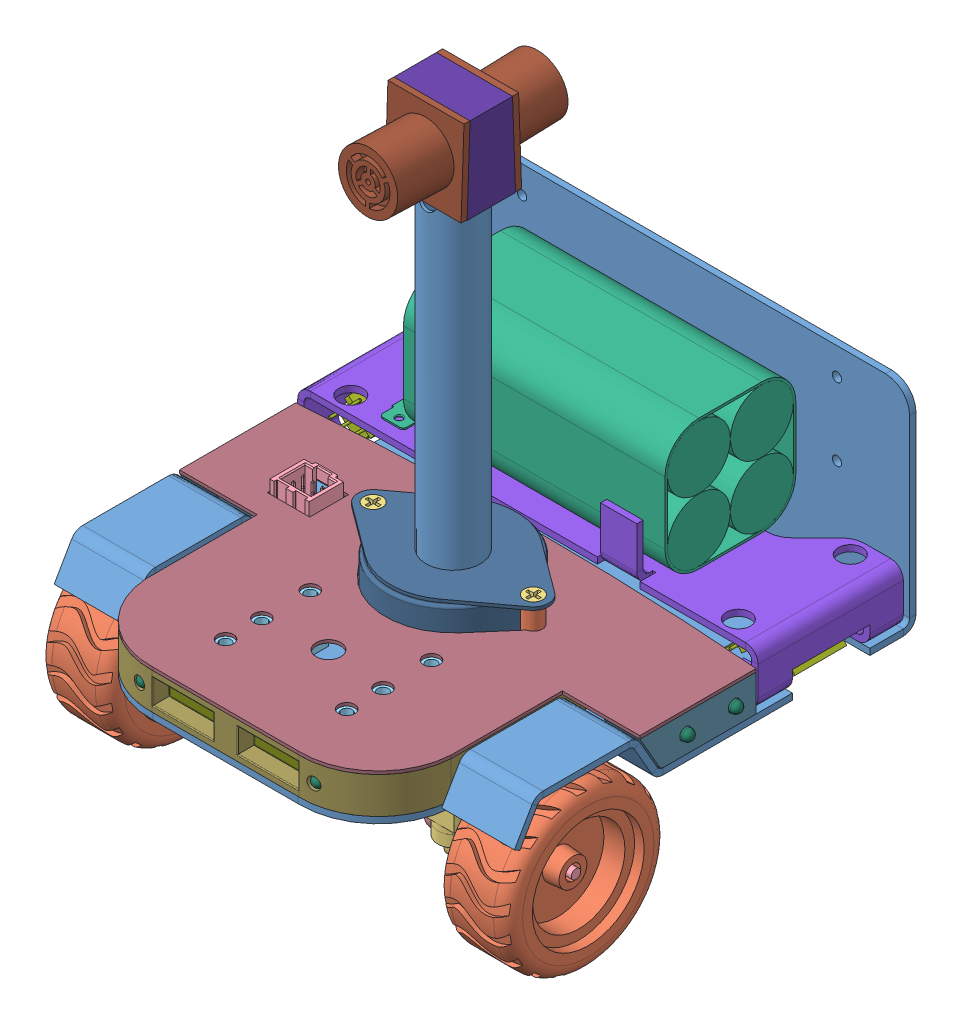
SolidWorks assembly REAR, TOP LEVEL, configuration Default. Lengths in mm.
Overall size (124.43 158.23 120.66).
44 component instances, 24 part files, 91 mates.
Components (placement in the parent):
- PLATE, REAR-1: PLATE, REAR [Default] at (-42.1312 28.0774 12.7174) size (120.65 55.63 120.66)
- WHEEL ASSEMBLY-1: WHEEL ASSEMBLY [Default-_flexible1] at (7.6153 26.9792 58.7651) x (0 0 1) z (1 0 0) size (42.46 78.6 70.03) (flexible)
  - Pololu 49x19 Wheel-1: Pololu 49x19 Wheel [Default] at (-19.8703 11.8393 2.4418) size (42.46 42.56 19)
  - Pololu Extended Micro Metal Bracket-1: Pololu Extended Micro Metal Bracket [Default] at (-19.8703 6.8393 -18.4366) size (26.6 22.49 26.04)
  - Pololu 298-1 Motor-1: Pololu 298-1 Motor [Default] at (-19.8703 11.8393 -25.1366) x (0 0 -1) z (0 1 0) size (35.87 12 10)
- WHEEL ASSEMBLY-2: WHEEL ASSEMBLY [Default-_flexible2] at (-91.8778 26.9792 19.0244) x (0 0 -1) z (-1 0 0) size (42.46 78.6 70.03) (flexible)
  - Pololu 49x19 Wheel-1: Pololu 49x19 Wheel [Default] at (-19.8703 11.8393 2.4418) size (42.46 42.56 19)
  - Pololu Extended Micro Metal Bracket-1: Pololu Extended Micro Metal Bracket [Default] at (-19.8703 6.8393 -18.4366) size (26.6 22.49 26.04)
  - Pololu 298-1 Motor-1: Pololu 298-1 Motor [Default] at (-19.8703 11.8393 -25.1366) x (0 0 -1) z (0 1 0) size (35.87 12 10)
- Socket Head Cap Screw_AI-1: Socket Head Cap Screw_AI [HX-SHCS 0.086-56x0.4375x0.4375-N] at (-77.6912 31.9128 47.8948) x (0 -1 0) z (-0.381305 0 -0.924449) size (13.3 3.56 3.56)
- Socket Head Cap Screw_AI-2: Socket Head Cap Screw_AI [HX-SHCS 0.086-56x0.4375x0.4375-N] at (-77.6912 31.9128 29.8948) x (0 -1 0) z (0 0 1) size (13.3 3.56 3.56)
- Socket Head Cap Screw_AI-3: Socket Head Cap Screw_AI [HX-SHCS 0.086-56x0.4375x0.4375-N] at (-6.5712 31.9128 29.8948) x (0 -1 0) z (0 0 1) size (13.3 3.56 3.56)
- Socket Head Cap Screw_AI-4: Socket Head Cap Screw_AI [HX-SHCS 0.086-56x0.4375x0.4375-N] at (-6.5712 31.9128 47.8948) x (0 -1 0) z (0 0 1) size (13.3 3.56 3.56)
- 4000mAh 7.4V Battery Pack-1: 4000mAh 7.4V Battery Pack [Default] at (-42.1312 61.2244 -25.7652) x (0 0 -1) z (1 0 0) size (34.29 34.29 68.58)
- SENSOR, GP2Y0D810-1: SENSOR, GP2Y0D810 [Default] at (9.9271 36.6454 -23.9419) x (0 0 -1) z (0.766044 0.642788 0) size (28.32 10.54 8.89)
- SENSOR, GP2Y0D810-2: SENSOR, GP2Y0D810 [Default] at (-94.1896 36.6454 -23.9419) x (0 0 -1) z (0.766044 -0.642788 0) size (28.32 10.54 8.89)
- Battery Support-1: Battery Support [Default] at (-42.1312 29.7284 -26.0192) size (120.65 27.05 38.1)
- Mounting Block-1: Mounting Block [Default] at (-42.1312 36.0784 -35.6712) x (-1 0 0) z (0 0 -1) size (25.4 12.7 25.4)
- PF35T-48-1: PF35T-48 [Default] at (-42.1312 31.7284 12.5888) size (50 29.2 35)
- MaxSonar EZ1-1: MaxSonar EZ1 [Default] at (-42.1312 140.4691 6.6293) x (-1 0 0) z (0 0.034899 -0.999391) size (19.94 22.1 16.38)
- MaxSonar EZ1-2: MaxSonar EZ1 [Default] at (-42.1312 140.4691 18.5483) x (1 0 0) z (0 0.034899 0.999391) size (19.94 22.1 16.38)
- BUMPER, REAR-1: BUMPER, REAR [Default] at (-42.1312 29.7284 53.2288) x (-1 0 0) z (0 0 -1) size (80.01 9.53 54.3)
- PLATE, REAR COVER-1: PLATE, REAR COVER [Default] at (-42.1312 39.2534 72.2788) size (120.65 0.81 81.14)
- MOUNTING BLOCK, COLOR SENSOR-1: MOUNTING BLOCK, COLOR SENSOR [Default] at (-97.6937 29.7284 5.6038) size (9.53 9.53 30.46)
- MOUNTING BLOCK, COLOR SENSOR-2: MOUNTING BLOCK, COLOR SENSOR [Default] at (13.4313 29.7284 5.6038) size (9.53 9.53 30.46)
- SENSOR, COLOR LED-1: SENSOR, COLOR LED [Default] at (-24.0807 23.782 31.9371) x (0 0 -1) z (-0.409692 -0.912224 0) size (5.83 3.66 3.66)
- SENSOR, COLOR LED-2: SENSOR, COLOR LED [Default] at (-67.3741 22.996 31.9371) x (0 0 -1) z (-0.202984 -0.979182 0) size (5.83 3.66 3.66)
- COPPER CONTACT-1: COPPER CONTACT [Default] at (-53.2437 34.4909 64.0238) size (15.88 6.35 4.45)
- COPPER CONTACT-2: COPPER CONTACT [Default] at (-31.0187 34.4909 64.0238) size (15.88 6.35 4.45)
- MOUNTING BLOCK, SONAR-1: MOUNTING BLOCK, SONAR [Default] at (-42.1312 140.3989 12.5888) x (-1 0 0) z (0 0 -1) size (19.94 22.23 12.7)
- SHAFT, SONAR MOUNT-1: SHAFT, SONAR MOUNT [Default] at (-42.1312 52.5784 12.5888) x (-0.538443 0 0.842662) z (-0.842662 0 -0.538443) size (4.76 89.41 4.76)
- SHAFT, SONAR SUPPORT-1: SHAFT, SONAR SUPPORT [Default] at (-42.1312 46.7284 12.5888) x (0.999987 0 0.005105) z (-0.005105 0 0.999987) size (14.22 82.87 14.22)
- SHAFT, STEPPER SUPPORT-1: SHAFT, STEPPER SUPPORT [Default] at (-63.1312 29.6724 12.5888) size (4.76 16.26 4.76)
- SHAFT, STEPPER SUPPORT-2: SHAFT, STEPPER SUPPORT [Default] at (-21.1312 29.6724 12.5888) x (0.987866 0 -0.155311) z (0.155311 0 0.987866) size (4.76 16.26 4.76)
- Flat Head 100 Screw_AI-2: Flat Head 100 Screw_AI [CR-FHM1 0.112-40x0.25x0.25-N] at (-63.1312 46.7284 12.5888) x (0 -1 0) z (0 0 1) size (6.35 4.85 4.85)
- Flat Head 100 Screw_AI-3: Flat Head 100 Screw_AI [CR-FHM1 0.112-40x0.25x0.25-N] at (-21.1312 46.7284 12.5888) x (0 -1 0) z (0 0 1) size (6.35 4.85 4.85)
- CONNECTOR, MOLEX 6 PIN-1: CONNECTOR, MOLEX 6 PIN [Default] at (-80.2263 37.7912 12.5433) size (10.34 13.8 9.75)
- SENSOR, COLOR LED-3: SENSOR, COLOR LED [Default] at (-64.0196 42.7147 3.5765) x (1 0 0) z (0 0.700538 -0.713616) size (5.83 3.66 3.66)
- SENSOR, COLOR LED-4: SENSOR, COLOR LED [Default] at (-64.0196 42.7147 -9.1235) x (1 0 0) z (0 0.700538 -0.713616) size (5.83 3.66 3.66)
- SENSOR, COLOR LED-5: SENSOR, COLOR LED [Default] at (-20.2429 42.7147 20.3311) x (-1 0 0) z (0 0.700538 0.713616) size (5.83 3.66 3.66)
- SENSOR, COLOR LED-6: SENSOR, COLOR LED [Default] at (-20.2429 42.7147 7.6311) x (-1 0 0) z (0 0.700538 0.713616) size (5.83 3.66 3.66)
- MOUNTING BLOCK, REAR-1: MOUNTING BLOCK, REAR [Default] at (-58.0062 34.4909 31.0038) size (9.53 9.53 28.57)
- MOUNTING BLOCK, REAR-2: MOUNTING BLOCK, REAR [Default] at (-26.2562 34.4909 31.0038) size (9.53 9.53 28.57)
- SW3dPS-Sliderswitch-1: SW3dPS-Sliderswitch [Standard] at (-81.1109 44.0794 -21.7288) size (7.4 16 23.2)
Mates (geometry in assembly coordinates):
- Coincident1: coincident aligned: plane of WHEEL ASSEMBLY-1/Pololu Extended Micro Metal Bracket-1 through (6.4788 20.1399 25.5948) normal (0 1 0); plane of WHEEL ASSEMBLY-2/Pololu Extended Micro Metal Bracket-1 through (-90.7412 20.1399 52.1948) normal (0 1 0)
- Coincident2: coincident anti-aligned: plane of PLATE, REAR-1 through (-82.1362 28.0774 18.9388) normal (0 -1 0); plane of WHEEL ASSEMBLY-2/Pololu Extended Micro Metal Bracket-1 through (-66.7356 28.0774 52.1948) normal (0 1 0)
- Coincident3: coincident aligned: plane of Socket Head Cap Screw_AI-1 through (-77.6912 31.9128 47.8948) normal (0 1 0); plane of Socket Head Cap Screw_AI-2 through (-77.6912 31.9128 29.8948) normal (0 1 0)
- Coincident4: coincident aligned: plane of Socket Head Cap Screw_AI-3 through (-6.5712 31.9128 29.8948) normal (0 1 0); plane of Socket Head Cap Screw_AI-4 through (-6.5712 31.9128 47.8948) normal (0 1 0)
- Coincident5: coincident aligned: plane of Socket Head Cap Screw_AI-2 through (-77.6912 31.9128 29.8948) normal (0 1 0); plane of Socket Head Cap Screw_AI-3 through (-6.5712 31.9128 29.8948) normal (0 1 0)
- Coincident6: coincident anti-aligned: plane of PLATE, REAR-1 through (-82.1362 29.7284 18.9388) normal (0 1 0); plane of Socket Head Cap Screw_AI-3 through (-4.7932 29.7284 29.8948) normal (0 -1 0)
- Concentric6: concentric aligned: cylinder of PLATE, REAR-1; cylinder of Socket Head Cap Screw_AI-2
- Concentric7: concentric aligned: cylinder of PLATE, REAR-1; cylinder of Socket Head Cap Screw_AI-1
- Concentric8: concentric aligned: cylinder of PLATE, REAR-1; cylinder of Socket Head Cap Screw_AI-3
- Concentric9: concentric aligned: cylinder of PLATE, REAR-1; cylinder of Socket Head Cap Screw_AI-4
- Concentric40: concentric aligned: cylinder of WHEEL ASSEMBLY-2/Pololu Extended Micro Metal Bracket-1; cylinder of Socket Head Cap Screw_AI-2
- Concentric41: concentric aligned: cylinder of WHEEL ASSEMBLY-2/Pololu Extended Micro Metal Bracket-1; cylinder of Socket Head Cap Screw_AI-1
- Concentric42: concentric aligned: cylinder of WHEEL ASSEMBLY-1/Pololu Extended Micro Metal Bracket-1; cylinder of Socket Head Cap Screw_AI-3
- Concentric43: concentric aligned: cylinder of WHEEL ASSEMBLY-1/Pololu Extended Micro Metal Bracket-1; cylinder of Socket Head Cap Screw_AI-4
- Coincident91: coincident aligned: plane of PLATE, REAR-1 through (-42.1312 28.0774 12.7174) normal (1 0 0); plane of 4000mAh 7.4V Battery Pack-1 through (-42.1312 61.2244 -25.7652) normal (1 0 0)
- Concentric44: concentric: cylinder of PLATE, REAR-1; cylinder of SENSOR, GP2Y0D810-2
- Parallel1: parallel: plane of PLATE, REAR-1 through (-97.7091 37.4434 -30.9045) normal (0 0 1); plane of SENSOR, GP2Y0D810-2 through (-89.7641 35.0043 -35.8291) normal (0 0 -1)
- Coincident93: coincident anti-aligned: plane of PLATE, REAR-1 through (1.6838 29.7284 -30.9045) normal (-0.642788 0.766044 0); plane of SENSOR, GP2Y0D810-1 through (6.522 33.7882 -35.8291) normal (0.642788 -0.766044 0)
- Concentric45: concentric aligned: cylinder of PLATE, REAR-1; cylinder of SENSOR, GP2Y0D810-1
- Parallel2: parallel aligned: plane of SENSOR, GP2Y0D810-1 through (12.3118 40.7187 -14.3661) normal (0.766044 0.642788 0); plane of PLATE, REAR-1 through (13.4467 37.4434 -35.9845) normal (0.766044 0.642788 0)
- Coincident97: coincident anti-aligned: plane of PLATE, REAR-1 through (-82.1362 29.7284 18.9388) normal (0 1 0); plane of Battery Support-1 through (18.1938 29.7284 -6.9692) normal (0 -1 0)
- Coincident98: coincident aligned: plane of PLATE, REAR-1 through (-42.1312 28.0774 12.7174) normal (1 0 0); plane of Battery Support-1 through (-42.1312 29.7284 -26.0192) normal (1 0 0)
- Coincident100: coincident aligned: plane of Battery Support-1 through (-89.7562 33.0304 -36.3062) normal (0 0 1); plane of PLATE, REAR-1 through (-102.4562 28.0774 -36.3062) normal (0 0 1)
- Coincident101: coincident anti-aligned: plane of 4000mAh 7.4V Battery Pack-1 through (-76.4212 69.4794 -8.6202) normal (0 0 1); plane of Battery Support-1 through (-23.0812 44.0794 -8.6202) normal (0 0 -1)
- Coincident102: coincident anti-aligned: plane of 4000mAh 7.4V Battery Pack-1 through (-76.4212 44.0794 -17.5102) normal (0 -1 0); plane of Battery Support-1 through (-102.4562 44.0794 -6.9692) normal (0 1 0)
- Coincident103: coincident anti-aligned: plane of PLATE, REAR-1 through (-82.1362 29.7284 18.9388) normal (0 1 0); plane of Mounting Block-1 through (-29.4312 29.7284 -48.3712) normal (0 -1 0)
- Concentric46: concentric aligned: cylinder of PLATE, REAR-1; cylinder of Mounting Block-1
- Concentric54: concentric aligned: cylinder of PLATE, REAR-1; cylinder of Mounting Block-1
- Coincident104: coincident anti-aligned: plane of PLATE, REAR-1 through (-82.1362 29.7284 18.9388) normal (0 1 0); plane of PF35T-48-1 through (-42.1312 29.7284 12.5888) normal (0 -1 0)
- Coincident105: coincident anti-aligned: plane of PLATE, REAR-1 through (-82.1362 29.7284 18.9388) normal (0 1 0); plane of BUMPER, REAR-1 through (-22.4072 29.7284 51.97) normal (0 -1 0)
- Coincident107: coincident aligned: plane of PLATE, REAR-1 through (-61.1812 28.0774 72.2788) normal (0 0 1); plane of BUMPER, REAR-1 through (-23.0812 39.2534 72.2788) normal (0 0 1)
- Concentric57: concentric anti-aligned: cylinder of PLATE, REAR-1; cylinder of BUMPER, REAR-1
- Coincident108: coincident anti-aligned: plane of BUMPER, REAR-1 through (-22.4072 39.2534 51.97) normal (0 1 0); plane of PLATE, REAR COVER-1 through (-61.8553 39.2534 51.97) normal (0 -1 0)
- Coincident109: coincident aligned: plane of PLATE, REAR-1 through (-61.1812 28.0774 72.2788) normal (0 0 1); plane of PLATE, REAR COVER-1 through (-23.0812 40.0662 72.2788) normal (0 0 1)
- Concentric58: concentric anti-aligned: cylinder of PLATE, REAR-1; cylinder of PLATE, REAR COVER-1
- Concentric59: concentric anti-aligned: cylinder of PF35T-48-1; cylinder of PLATE, REAR COVER-1
- Coincident110: coincident aligned: plane of MOUNTING BLOCK, COLOR SENSOR-1 through (-92.9312 39.2534 -6.4612) normal (0 1 0); plane of MOUNTING BLOCK, COLOR SENSOR-2 through (18.1938 39.2534 -6.4612) normal (0 1 0)
- Coincident111: coincident anti-aligned: plane of PLATE, REAR-1 through (-82.1362 29.7284 18.9388) normal (0 1 0); plane of MOUNTING BLOCK, COLOR SENSOR-1 through (-92.9312 29.7284 -6.4612) normal (0 -1 0)
- Coincident112: coincident aligned: plane of MOUNTING BLOCK, COLOR SENSOR-1 through (-102.4562 39.2534 -6.4612) normal (0 0 -1); plane of MOUNTING BLOCK, COLOR SENSOR-2 through (8.6688 39.2534 -6.4612) normal (0 0 -1)
- Coincident113: coincident: line of PLATE, REAR-1; plane of MOUNTING BLOCK, COLOR SENSOR-1 through (-102.4562 39.2534 17.6688) normal (-1 0 0)
- Coincident114: coincident aligned: plane of PLATE, REAR-1 through (18.1938 29.7284 18.9388) normal (1 0 0); plane of MOUNTING BLOCK, COLOR SENSOR-2 through (18.1938 39.2534 17.6688) normal (1 0 0)
- Coincident115: coincident aligned: line of MOUNTING BLOCK, COLOR SENSOR-2; line of PLATE, REAR COVER-1
- Concentric60: concentric anti-aligned: cylinder of PF35T-48-1; cylinder of PLATE, REAR COVER-1
- Coincident117: coincident aligned: plane of MaxSonar EZ1-1 through (-52.1007 129.4822 4.6572) normal (-1 0 0); plane of MaxSonar EZ1-2 through (-52.1007 129.4822 20.5204) normal (-1 0 0)
- Concentric62: concentric aligned: cylinder of BUMPER, REAR-1; cylinder of SENSOR, COLOR LED-1
- Concentric63: concentric aligned: cylinder of BUMPER, REAR-1; cylinder of SENSOR, COLOR LED-2
- Coincident120: coincident aligned: plane of COPPER CONTACT-1 through (-45.3062 37.6659 68.4688) normal (0 0 1); plane of COPPER CONTACT-2 through (-23.0812 37.6659 68.4688) normal (0 0 1)
- Coincident121: coincident aligned: plane of COPPER CONTACT-1 through (-61.1812 37.6659 68.4688) normal (0 1 0); plane of COPPER CONTACT-2 through (-38.9562 37.6659 68.4688) normal (0 1 0)
- Coincident122: coincident anti-aligned: plane of BUMPER, REAR-1 through (-38.9562 31.3159 72.29) normal (0 1 0); plane of COPPER CONTACT-2 through (-38.9562 31.3159 68.4688) normal (0 -1 0)
- Coincident123: coincident anti-aligned: plane of BUMPER, REAR-1 through (-23.0812 31.3159 72.29) normal (-1 0 0); plane of COPPER CONTACT-2 through (-23.0812 31.3159 68.4688) normal (1 0 0)
- Coincident124: coincident anti-aligned: plane of BUMPER, REAR-1 through (-61.1812 31.3159 72.29) normal (1 0 0); plane of COPPER CONTACT-1 through (-61.1812 31.3159 68.4688) normal (-1 0 0)
- Distance3: distance = 3.81 mm aligned: plane of COPPER CONTACT-2 through (-23.0812 37.6659 68.4688) normal (0 0 1); plane of BUMPER, REAR-1 through (-23.0812 39.2534 72.2788) normal (0 0 1)
- Coincident125: coincident anti-aligned: plane of MaxSonar EZ1-1 through (-52.1007 151.5114 7.0149) normal (0 -0.034899 0.999391); plane of MOUNTING BLOCK, SONAR-1 through (-32.1617 129.2864 6.2388) normal (0 0.034899 -0.999391)
- Coincident126: coincident aligned: plane of MaxSonar EZ1-1 through (-52.1007 129.4822 4.6572) normal (-1 0 0); plane of MOUNTING BLOCK, SONAR-1 through (-52.1007 129.2864 6.2388) normal (-1 0 0)
- Concentric64: concentric aligned: cylinder of PF35T-48-1; cylinder of MOUNTING BLOCK, SONAR-1
- Coincident129: coincident anti-aligned: plane of PF35T-48-1 through (-42.1312 58.9284 12.5888) normal (0 1 0); plane of SHAFT, SONAR MOUNT-1 through (-42.1312 58.9284 12.5888) normal (0 -1 0)
- Concentric65: concentric aligned: cylinder of PF35T-48-1; cylinder of SHAFT, SONAR MOUNT-1
- Concentric66: concentric aligned: cylinder of SHAFT, SONAR MOUNT-1; cylinder of SHAFT, SONAR SUPPORT-1
- Coincident130: coincident anti-aligned: plane of PF35T-48-1 through (-63.1312 46.7284 12.5888) normal (0 1 0); plane of SHAFT, SONAR SUPPORT-1 through (-42.1312 46.7284 12.5888) normal (0 -1 0)
- Concentric67: concentric anti-aligned: cylinder of PLATE, REAR COVER-1; cylinder of SHAFT, STEPPER SUPPORT-1
- Concentric68: concentric anti-aligned: cylinder of PLATE, REAR COVER-1; cylinder of SHAFT, STEPPER SUPPORT-2
- Coincident131: coincident anti-aligned: plane of PF35T-48-1 through (-63.1312 45.9284 12.5888) normal (0 -1 0); plane of SHAFT, STEPPER SUPPORT-1 through (-63.1312 45.9284 12.5888) normal (0 1 0)
- Coincident132: coincident anti-aligned: plane of PF35T-48-1 through (-63.1312 45.9284 12.5888) normal (0 -1 0); plane of SHAFT, STEPPER SUPPORT-2 through (-21.1312 45.9284 12.5888) normal (0 1 0)
- Coincident133: coincident aligned: plane of Flat Head 100 Screw_AI-2 through (-61.7088 40.3784 12.5888) normal (0 -1 0); plane of Flat Head 100 Screw_AI-3 through (-19.7088 40.3784 12.5888) normal (0 -1 0)
- Concentric69: concentric anti-aligned: cylinder of SHAFT, STEPPER SUPPORT-2; cylinder of Flat Head 100 Screw_AI-3
- Concentric70: concentric anti-aligned: cylinder of SHAFT, STEPPER SUPPORT-1; cylinder of Flat Head 100 Screw_AI-2
- Coincident134: coincident aligned: plane of PF35T-48-1 through (-63.1312 46.7284 12.5888) normal (0 1 0); plane of Flat Head 100 Screw_AI-2 through (-63.1312 46.7284 12.5888) normal (0 1 0)
- Coincident135: coincident aligned: plane of SENSOR, COLOR LED-3 through (-98.5192 37.1081 11.9296) normal (1 0 0); plane of SENSOR, COLOR LED-4 through (-98.5192 37.1081 -0.7704) normal (1 0 0)
- Coincident136: coincident aligned: plane of SENSOR, COLOR LED-5 through (14.2568 37.1081 11.978) normal (-1 0 0); plane of SENSOR, COLOR LED-6 through (14.2568 37.1081 -0.722) normal (-1 0 0)
- Concentric71: concentric anti-aligned: cylinder of MOUNTING BLOCK, COLOR SENSOR-2; cylinder of SENSOR, COLOR LED-6
- Concentric72: concentric anti-aligned: cylinder of MOUNTING BLOCK, COLOR SENSOR-2; cylinder of SENSOR, COLOR LED-5
- Distance5: distance = 3.175 mm aligned: plane of SENSOR, COLOR LED-5 through (15.0188 34.5151 9.3365) normal (1 0 0); plane of MOUNTING BLOCK, COLOR SENSOR-2 through (18.1938 39.2534 17.6688) normal (1 0 0)
- Concentric73: concentric aligned: cylinder of SENSOR, COLOR LED-4; cylinder of MOUNTING BLOCK, COLOR SENSOR-1
- Concentric74: concentric aligned: cylinder of MOUNTING BLOCK, COLOR SENSOR-1; cylinder of SENSOR, COLOR LED-3
- Distance6: distance = 3.175 mm aligned: plane of SENSOR, COLOR LED-4 through (-99.2812 34.5151 1.871) normal (-1 0 0); plane of MOUNTING BLOCK, COLOR SENSOR-1 through (-102.4562 39.2534 17.6688) normal (-1 0 0)
- Distance7: distance = 3.175 mm aligned: plane of CONNECTOR, MOLEX 6 PIN-1 through (-74.8495 43.2412 7.4733) normal (0 1 0); plane of PLATE, REAR COVER-1 through (-61.8553 40.0662 51.97) normal (0 1 0)
- Coincident137: coincident anti-aligned: plane of MOUNTING BLOCK, SONAR-1 through (-42.1312 141.9864 12.5888) normal (0 -1 0); plane of SHAFT, SONAR MOUNT-1 through (-42.1312 141.9864 12.5888) normal (0 1 0)
- Coincident138: coincident aligned: plane of MOUNTING BLOCK, REAR-1 through (-62.7687 39.2534 59.5788) normal (0 1 0); plane of MOUNTING BLOCK, REAR-2 through (-31.0187 39.2534 59.5788) normal (0 1 0)
- Coincident139: coincident aligned: plane of MOUNTING BLOCK, REAR-1 through (-53.2437 39.2534 31.0038) normal (0 0 -1); plane of MOUNTING BLOCK, REAR-2 through (-21.4937 39.2534 31.0038) normal (0 0 -1)
- Coincident140: coincident anti-aligned: plane of PLATE, REAR-1 through (-82.1362 29.7284 18.9388) normal (0 1 0); plane of MOUNTING BLOCK, REAR-1 through (-62.7687 29.7284 59.5788) normal (0 -1 0)
- Concentric75: concentric aligned: cylinder of PLATE, REAR COVER-1; cylinder of MOUNTING BLOCK, REAR-1
- Concentric76: concentric aligned: cylinder of PLATE, REAR COVER-1; cylinder of MOUNTING BLOCK, REAR-1
- Concentric77: concentric aligned: cylinder of PLATE, REAR COVER-1; cylinder of MOUNTING BLOCK, REAR-2
- Coincident144: coincident anti-aligned: plane of MaxSonar EZ1-2 through (-32.1617 151.5114 18.1627) normal (0 -0.034899 -0.999391); plane of MOUNTING BLOCK, SONAR-1 through (-32.1617 129.2864 18.9388) normal (0 0.034899 0.999391)
- Coincident146: coincident: plane of MaxSonar EZ1-1 through (-32.1617 151.5668 5.4284) normal (0 0.999391 0.034899); line of MOUNTING BLOCK, SONAR-1
- Coincident147: coincident: plane of MaxSonar EZ1-2 through (-52.1007 151.5668 19.7492) normal (0 0.999391 -0.034899); line of MOUNTING BLOCK, SONAR-1
- Angle1: planar angle = 3.141593 rad aligned: plane of MOUNTING BLOCK, SONAR-1 through (-52.1007 129.2864 6.2388) normal (-1 0 0); plane of MOUNTING BLOCK, COLOR SENSOR-2 through (18.1938 39.2534 17.6688) normal (1 0 0)
- Coincident148: coincident aligned: plane of SENSOR, COLOR LED-1 through (-21.7178 33.5608 66.4368) normal (0 0 -1); plane of SENSOR, COLOR LED-2 through (-67.1791 33.0543 66.4368) normal (0 0 -1)
- Distance8: distance = 3.81 mm anti-aligned: plane of SENSOR, COLOR LED-1 through (-20.2013 36.9374 67.1988) normal (0 0 1); plane of BUMPER, REAR-1 through (-22.9127 39.2534 63.3888) normal (0 0 -1)
- Coincident149: coincident anti-aligned: plane of PLATE, REAR-1 through (-85.9462 29.7284 -30.9045) normal (0.642788 0.766044 0); plane of SENSOR, GP2Y0D810-2 through (-97.5946 39.5026 -35.8291) normal (-0.642788 -0.766044 0)
- Coincident150: coincident anti-aligned: plane of PLATE, REAR COVER-1; plane of PLATE, REAR-1
